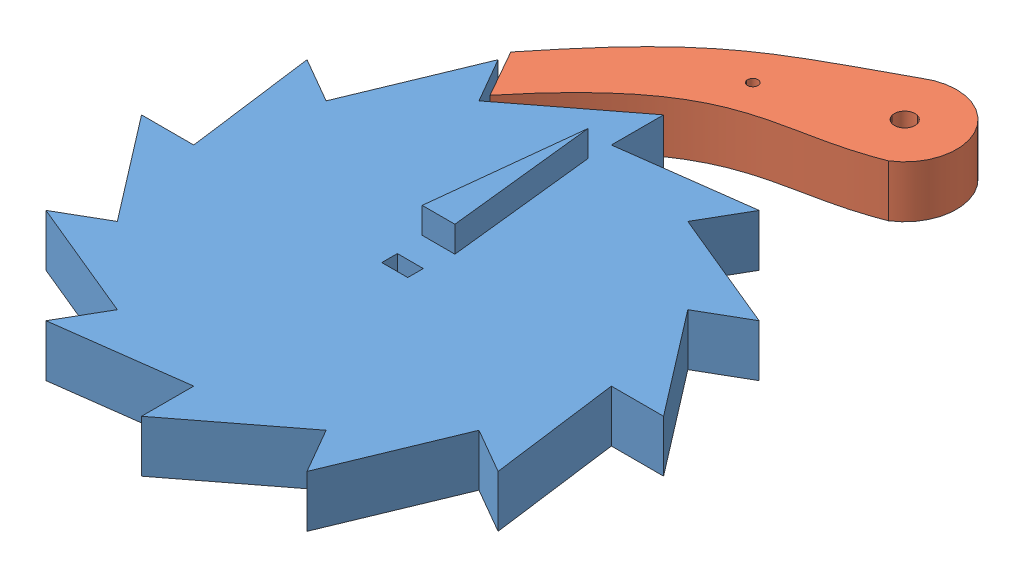
SolidWorks assembly Assembly, configuration Default. Lengths in mm.
Overall size (100.56 15 133).
2 component instances, 2 part files, 1 mates.
Components (placement in the parent):
- Gear-1: Gear [Default] at (30.3963 41.7908 88.2147) size (100.56 15 100.56)
- Prawl-1: Prawl [Default] at (54.3966 41.7908 15.4899) size (59.2 10 45.9)
Mates (geometry in assembly coordinates):
- Coincident1: coincident aligned: plane of Gear-1 through (30.3963 51.7908 88.2147) normal (0 1 0); plane of Prawl-1 through (36.8667 51.7908 30.0442) normal (0 1 0)
